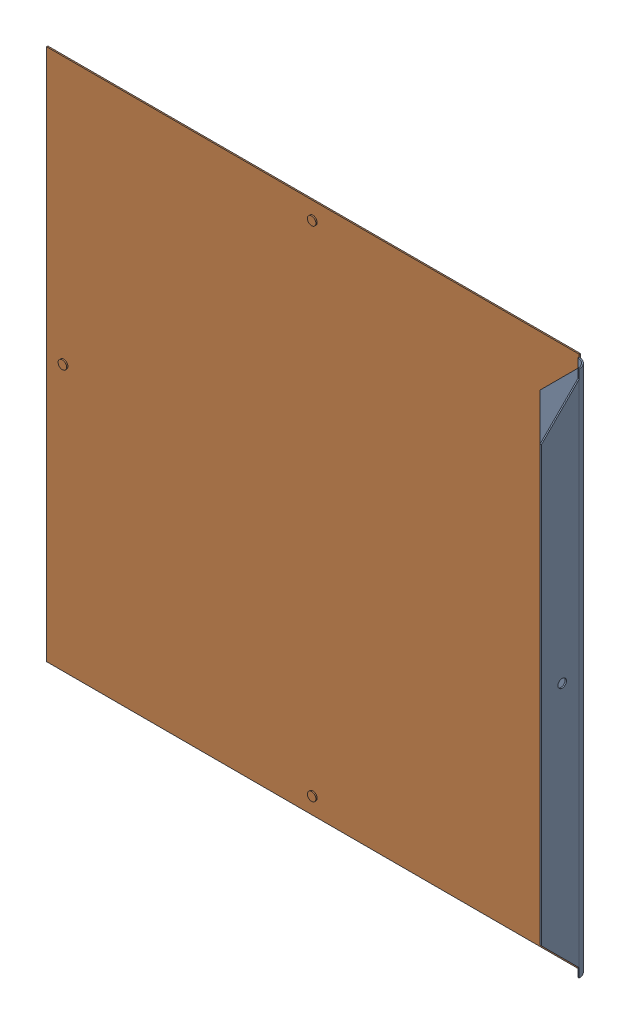
SolidWorks assembly inner_bracket_flat, configuration Default. Lengths in mm.
Overall size (638 626 58).
2 component instances, 2 part files, 2 mates.
Components (placement in the parent):
- inner_bracket-1: inner_bracket [Default] at (29.8639 -5.69 30.8251) size (56.5 620 56.5)
- inner_flat-1: inner_flat [Default] at (-293.6361 -5.69 -25.6749) x (1 0 0) z (0 0 -1) size (626 626 3)
Mates (geometry in assembly coordinates):
- Concentric1: concentric: circle of inner_bracket-1; circle of inner_flat-1
- Coincident2: coincident anti-aligned: plane of inner_bracket-1 through (31.3639 -5.69 -25.6749) normal (0 0 -1); plane of inner_flat-1 through (-293.6361 -5.69 -25.6749) normal (0 0 1)
